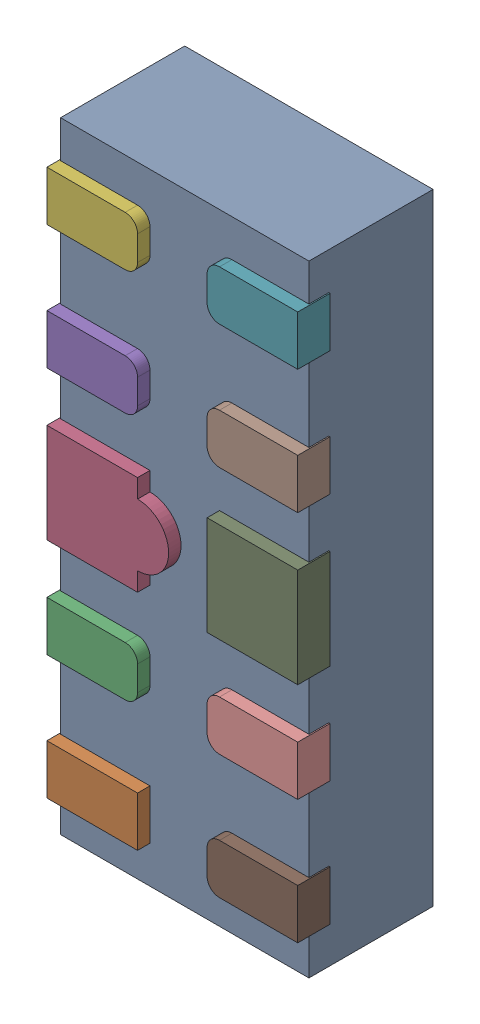
SolidWorks assembly D42, configuration Défaut. Lengths in mm.
Overall size (1.01 2.5 0.55).
12 component instances, 5 part files, 0 mates.
Components (placement in the parent):
- UDFN10-1: UDFN10 [Défaut] at (77.4175 -21.6272 -1.1719) x (0 1 0) z (-1 0 0) size (2.5 0.55 1.01)
  - User Library-UDFN10_Body-1: User Library-UDFN10_Body [Défaut] at (1.0785 0.9721 1.8983) size (2.5 0.5 1)
  - User Library-UDFN10_Pin1-1: User Library-UDFN10_Pin1 [Défaut] at (0.0785 1.0521 2.2208) x (0 0 -1) z (-1 0 0) size (0.37 0.13 0.2)
  - User Library-UDFN10_Pin2-1: User Library-UDFN10_Pin2 [Défaut] at (0.5785 1.0521 2.2208) x (0 0 1) z (1 0 0) size (0.37 0.13 0.2)
  - User Library-UDFN10_Pin4-1: User Library-UDFN10_Pin4 [Défaut] at (1.0785 0.9221 2.2208) x (0 0 1) z (-1 0 0) size (0.49 0.13 0.4)
  - User Library-UDFN10_Pin2-2: User Library-UDFN10_Pin2 [Défaut] at (1.5785 0.9221 2.2208) x (0 0 1) z (-1 0 0) size (0.37 0.13 0.2)
  - User Library-UDFN10_Pin2-3: User Library-UDFN10_Pin2 [Défaut] at (2.0785 0.9221 2.2208) x (0 0 1) z (-1 0 0) size (0.37 0.13 0.2)
  - User Library-UDFN10_Pin2-4: User Library-UDFN10_Pin2 [Défaut] at (2.0785 0.9221 1.5758) x (0 0 -1) z (1 0 0) size (0.37 0.13 0.2)
  - User Library-UDFN10_Pin2-5: User Library-UDFN10_Pin2 [Défaut] at (1.5785 0.9221 1.5758) x (0 0 -1) z (1 0 0) size (0.37 0.13 0.2)
  - User Library-UDFN10_Pin3-1: User Library-UDFN10_Pin3 [Défaut] at (1.0785 0.9221 1.5758) x (0 0 1) z (-1 0 0) size (0.37 0.13 0.4)
  - User Library-UDFN10_Pin2-6: User Library-UDFN10_Pin2 [Défaut] at (0.5785 0.9221 1.5758) x (0 0 -1) z (1 0 0) size (0.37 0.13 0.2)
  - User Library-UDFN10_Pin2-7: User Library-UDFN10_Pin2 [Défaut] at (0.0785 0.9221 1.5758) x (0 0 -1) z (1 0 0) size (0.37 0.13 0.2)
